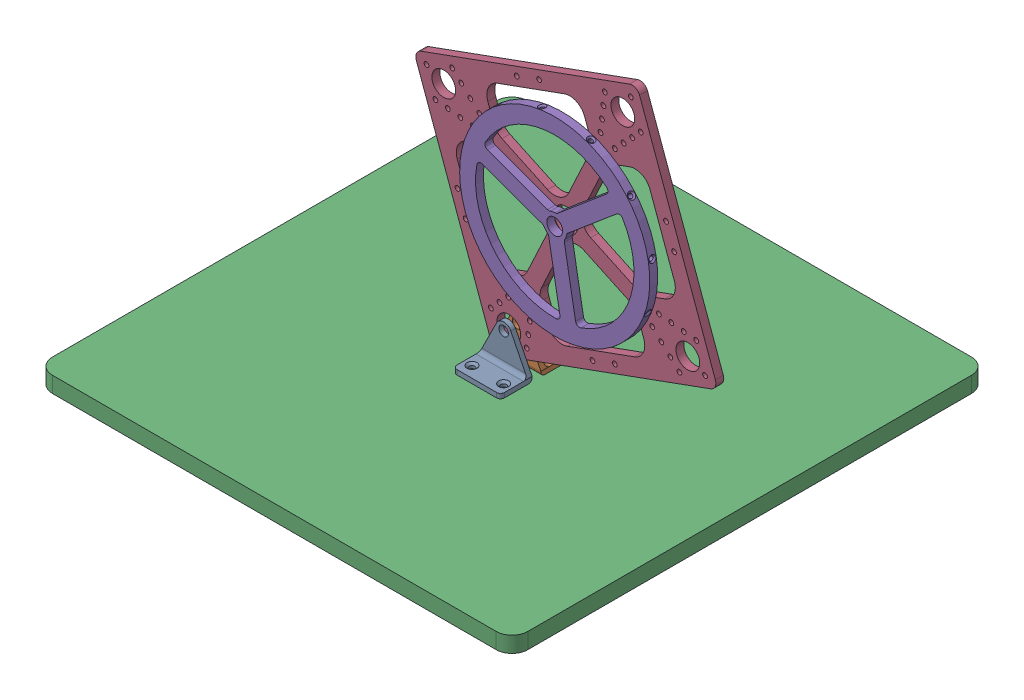
SolidWorks assembly Assem1, configuration Default. Lengths in mm.
Overall size (300 204.94 300).
5 component instances, 4 part files, 10 mates.
Components (placement in the parent):
- Hinges-1: Hinges [Default] at (63.4611 -43.204 -64.1966) x (0 0 -1) z (1 0 0) size (20 26.82 30)
- Hinges-2: Hinges [Default] at (63.4611 -43.204 -89.6966) x (0 0 1) z (-1 0 0) size (20 26.82 30)
- Stand-1: Stand [Default] at (63.4611 -53.204 -76.4466) size (300 10 300)
- Pendulum_Body-1: Pendulum_Body [Default] at (99.4234 55.6333 -79.4466) x (0.939869 0.341534 0) z (0 0 1) size (150 150 5)
- Reaction_Wheel-1: Reaction_Wheel [Default] at (99.4234 55.6333 -72.4466) x (-0.340334 -0.940305 0) z (0 0 1) size (120 120 5)
Mates (geometry in assembly coordinates):
- Coincident1: coincident aligned: plane of Hinges-1 through (78.4611 -40.204 -74.1966) normal (1 0 0); plane of Hinges-2 through (78.4611 -40.204 -79.6966) normal (1 0 0)
- Coincident2: coincident aligned: plane of Hinges-1 through (63.4611 -40.204 -64.1966) normal (0 1 0); plane of Hinges-2 through (63.4611 -40.204 -89.6966) normal (0 1 0)
- Distance1: distance = 5.5 mm anti-aligned: plane of Hinges-2 through (78.4611 -40.204 -79.6966) normal (0 0 1); plane of Hinges-1 through (48.4611 -40.204 -74.1966) normal (0 0 -1)
- Coincident4: coincident anti-aligned: plane of Hinges-1 through (63.4611 -43.204 -64.1966) normal (0 -1 0); plane of Stand-1 through (-76.5389 -43.204 63.5534) normal (0 1 0)
- Distance2: distance = 135 mm aligned: plane of Hinges-1 through (78.4611 -40.204 -74.1966) normal (1 0 0); plane of Stand-1 through (213.4611 -43.204 -216.4466) normal (1 0 0)
- Distance3: distance = 127.75 mm aligned: plane of Hinges-1 through (48.4611 -40.204 -54.1966) normal (0 0 1); plane of Stand-1 through (203.4611 -43.204 73.5534) normal (0 0 1)
- Concentric1: concentric anti-aligned: circle of Hinges-1; circle of Pendulum_Body-1
- Distance4: distance = 0.25 mm anti-aligned: plane of Pendulum_Body-1 through (189.1217 13.7498 -74.4466) normal (0 0 1); plane of Hinges-1 through (48.4611 -40.204 -74.1966) normal (0 0 -1)
- Concentric2: concentric aligned: circle of Pendulum_Body-1; circle of Reaction_Wheel-1
- Distance5: distance = 2 mm anti-aligned: plane of Reaction_Wheel-1 through (99.4234 55.6333 -72.4466) normal (0 0 -1); plane of Pendulum_Body-1 through (189.1217 13.7498 -74.4466) normal (0 0 1)
